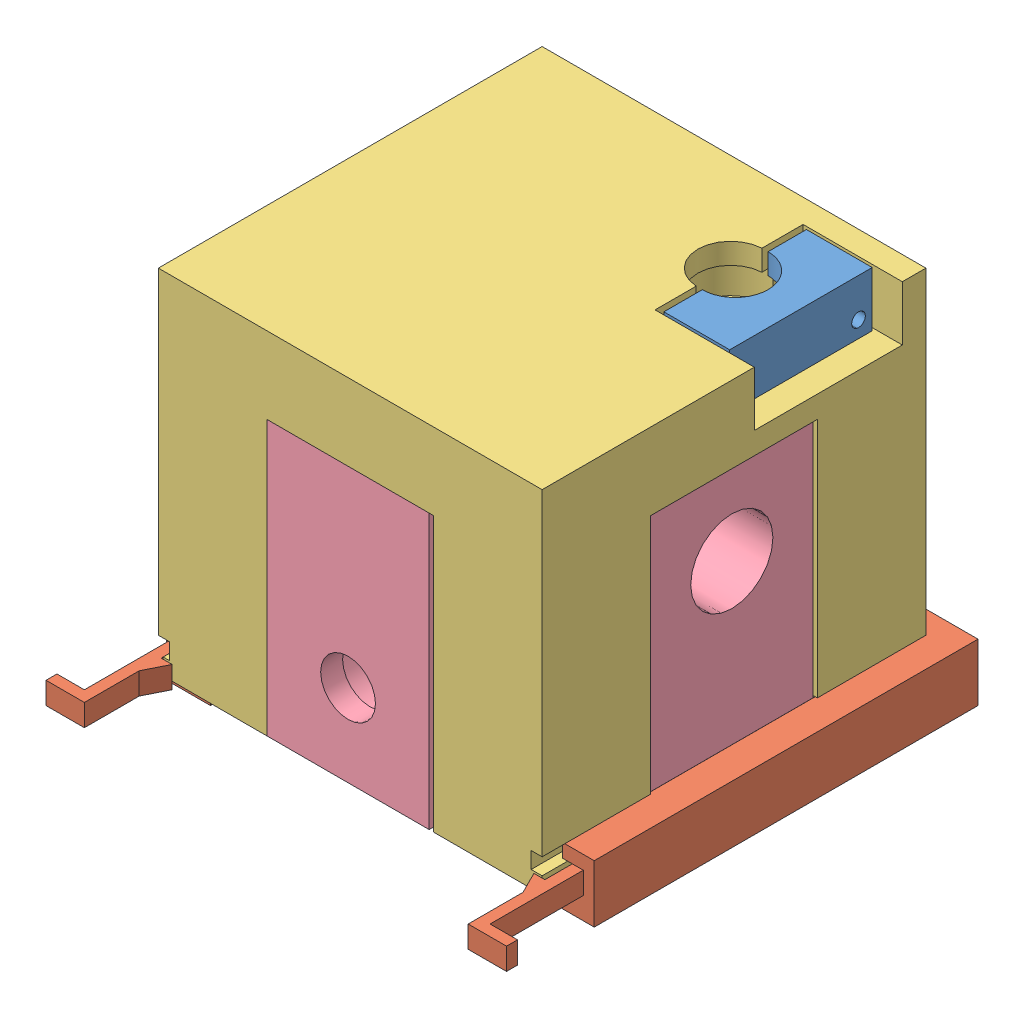
SolidWorks assembly Tête_complete, configuration Défaut. Lengths in mm.
Overall size (84 69 89).
4 component instances, 4 part files, 3 mates.
Components (placement in the parent):
- Clip_Buse_E3D-1: Clip_Buse_E3D [Défaut] at (17.0518 23.4109 40.0035) x (1 0 0) z (0 1 0) size (12 26 10)
- Clip_Porte_Buse_E3D-1: Clip_Porte_Buse_E3D [Défaut] at (26.9018 -25.0891 4.5597) x (1 0 0) z (0 -1 0) size (84 89 10.5)
- Porte_Buse_E3D_V2-1: Porte_Buse_E3D_V2 [Défaut] at (22.03 33.4019 79.1927) x (0 0 1) z (0 -1 0) size (70 70 64)
- Chariot-1: Chariot [Défaut] at (-48.37 -30.5981 79.1927) size (70 50 70)
Mates (geometry in assembly coordinates):
- Coïncidente19: coincident: plane of Porte_Buse_E3D_V2-1 through (22.03 19.4019 79.1927) normal (0 -1 0); plane of Chariot-1 through (21.63 19.4019 79.1927) normal (0 1 0)
- Coïncidente20: coincident: plane of Porte_Buse_E3D_V2-1 through (-28.17 19.4019 79.1927) normal (1 0 0); plane of Chariot-1 through (-28.17 19.4019 79.1927) normal (-1 0 0)
- Coïncidente21: coincident aligned: plane of Porte_Buse_E3D_V2-1 through (22.03 -30.5981 79.1927) normal (0 0 1); plane of Chariot-1 through (21.63 -30.5981 79.1927) normal (0 0 1)
